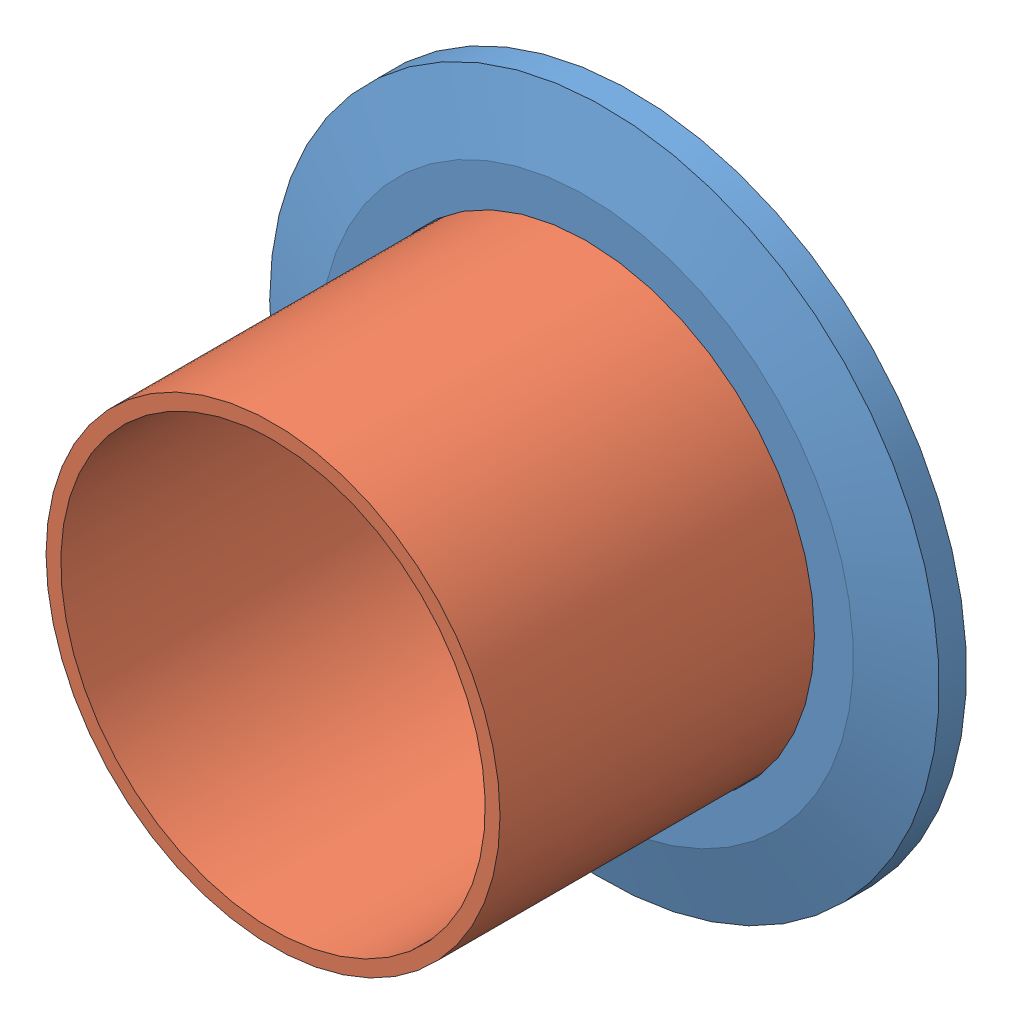
SolidWorks assembly 715109-REV.B, configuration Default. Lengths in mm.
Overall size (74.93 74.93 40.14).
2 component instances, 2 part files, 2 mates.
Components (placement in the parent):
- 713022-1: 713022 [Default] at (54.2462 -60.375 78.418) size (74.93 74.93 5.08)
- 971504-REV.B-1: 971504-REV.B [Default] at (54.2462 -60.375 82.487) x (-0.063338 0.997992 0) z (0 0 1) size (50.8 50.8 36.07)
Mates (geometry in assembly coordinates):
- Concentric1: concentric: cylinder of 713022-1 through (54.2462 -60.375 78.418) axis (0 0 -1) radius 23.749; cylinder of 971504-REV.B-1 through (54.2462 -60.375 118.555) axis (0 0 -1) radius 25.4
- Parallel1: parallel anti-aligned: plane of 713022-1 through (77.9952 -60.375 82.482) normal (0 0 1); plane of 971504-REV.B-1 through (54.2462 -60.375 82.487) normal (0 0 -1)
